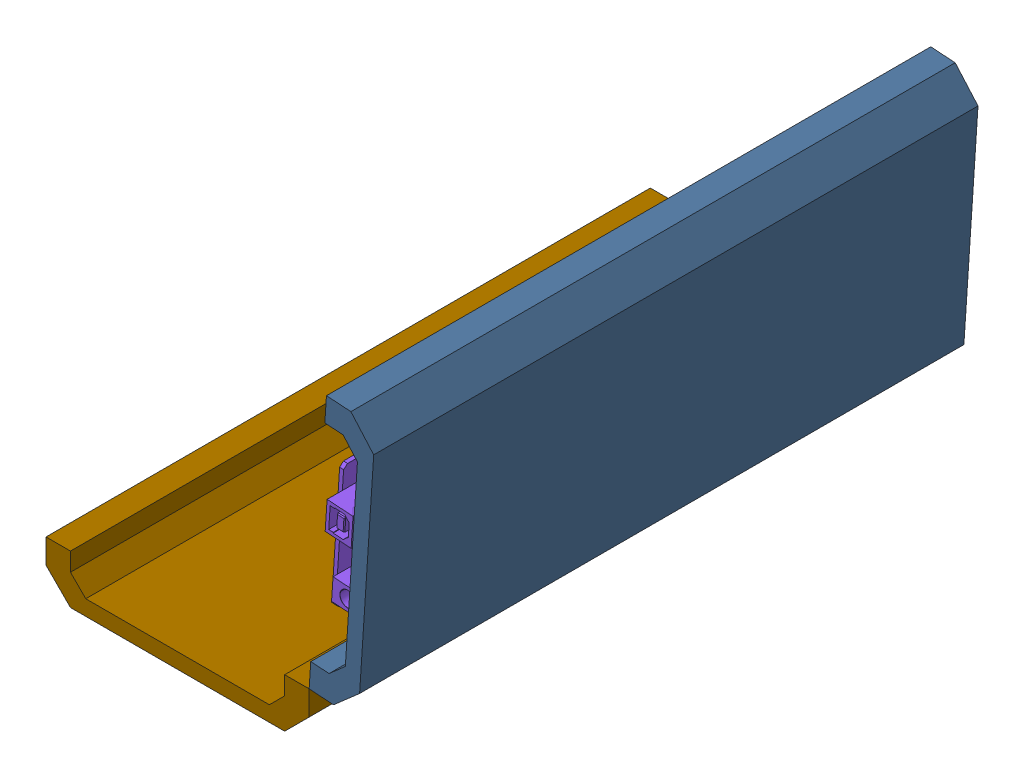
SolidWorks assembly blacktopTestJig, configuration Default. Lengths in mm.
Overall size (136.69 129.3 250.82).
19 component instances, 10 part files, 12 mates.
Components (placement in the parent):
- base-1: base [Default] at (-12.9077 -6.715 39.8526) size (63.5 1.59 96.52)
- MSP-EXP430G2ET-1: MSP-EXP430G2ET [Default] at (-12.9077 1.667 -16.0274) size (58.42 18.61 78.74)
- blacktop02.step-1: blacktop02.step [Default] at (-162.7677 0.335 -47.7774) x (1 0 0) z (0 1 0) size (50.8 33.02 10.45)
  - SOIC-8_3.9x4.9mm_P1.27mm.step-1: SOIC-8_3.9x4.9mm_P1.27mm.step [Default] at (159.385 -75.8825 1.65) x (0 1 0) z (0 0 1) size (6 4.9 1.75)
    - SOLID.step-1: SOLID.step [Default] at origin size (6 4.9 1.75)
  - TSSOP-28_4.4x9.7mm_P0.65mm.step-1: TSSOP-28_4.4x9.7mm_P0.65mm.step [Default] at (136.491 -75.89 1.65) x (0 -1 0) z (0 0 1) size (6.4 9.7 1.1)
    - SOLID-0.step-1: SOLID-0.step [Default] at origin size (6.4 9.7 1.1)
  - PinSocket_1x10_P2.54mm_Vertical.step-1: PinSocket_1x10_P2.54mm_Vertical.step [Default] at (172.72 -76.2 -0.05) x (-1 0 0) z (0 0 -1) size (2.54 25.4 10.1)
    - SOLID-1.step-1: SOLID-1.step [Default] at origin size (2.54 25.4 10.1)
  - PinSocket_1x10_P2.54mm_Vertical.step-2: PinSocket_1x10_P2.54mm_Vertical.step [Default] at (127 -76.2 -0.05) x (-1 0 0) z (0 0 -1) size (2.54 25.4 10.1)
    - SOLID-1.step-1: SOLID-1.step [Default] at origin size (2.54 25.4 10.1)
  - C_0603_1608Metric.step-1: C_0603_1608Metric.step [Default] at (158.355 -71.12 1.65) size (1.6 0.8 0.8)
    - SOLID-2.step-1: SOLID-2.step [Default] at origin size (1.6 0.8 0.8)
  - C_0603_1608Metric.step-2: C_0603_1608Metric.step [Default] at (141.5936 -71.12 1.65) x (-1 0 0) z (0 0 1) size (1.6 0.8 0.8)
    - SOLID-2.step-1: SOLID-2.step [Default] at origin size (1.6 0.8 0.8)
  - COMPOUND.step-1: COMPOUND.step [Default] at origin size (50.8 33.02 1.6)
- ArduinoMega-1: ArduinoMega [Default] at (45.9223 52.9564 120.3261) x (0 0 1) z (-0.99783 0.065837 0) size (107.95 53.42 12.95)
- CaseLower-1: CaseLower [Default] at (5.242 -1.7477 26.9005) size (109.22 20.32 250.82)
- CaseUpper-1: CaseUpper [Default] at (56.0378 57.4931 40.42) x (0.065837 0.99783 0) z (0 0 1) size (109.22 20.32 250.83)
Mates (geometry in assembly coordinates):
- Coincident1: coincident anti-aligned: line of base-1 through (11.2223 -6.715 -3.3274) axis (0 0 -1); line of MSP-EXP430G2ET-1 through (11.2223 -6.715 -28.7274) axis (0 0 1)
- Coincident2: coincident aligned: line of base-1 through (11.2223 -6.715 -3.3274) axis (-1 0 0); line of MSP-EXP430G2ET-1 through (11.2223 -6.715 -3.3274) axis (-1 0 0)
- Coincident3: coincident anti-aligned: line of base-1 through (11.2223 -6.715 52.5526) axis (0 0 -1); line of blacktop02.step-1/PinSocket_1x10_P2.54mm_Vertical.step-1/SOLID-1.step-1 through (11.2223 -6.715 27.1526) axis (0 0 1)
- Coincident4: coincident aligned: line of base-1 through (11.2223 -6.715 52.5526) axis (-1 0 0); line of blacktop02.step-1/PinSocket_1x10_P2.54mm_Vertical.step-1/SOLID-1.step-1 through (11.2223 -6.715 52.5526) axis (-1 0 0)
- Coincident5: coincident anti-aligned: plane of base-1 through (-42.1177 -8.3025 57.6326) normal (0 -1 0); plane of CaseLower-1 through (15.0323 -8.3025 -32.5374) normal (0 1 0)
- Concentric1: concentric aligned: circle of base-1; circle of CaseLower-1
- Concentric2: concentric aligned: circle of base-1; circle of CaseLower-1
- Coincident6: coincident aligned: line of CaseLower-1 through (41.7023 0.5875 -71.2724) axis (0 0 1); line of CaseUpper-1 through (41.7023 0.5875 -71.2724) axis (0 0 1)
- Coincident7: coincident: point of CaseLower-1; point of CaseUpper-1
- Parallel1: parallel anti-aligned: plane of ArduinoMega-1 through (44.1639 26.3063 171.1261) normal (0.99783 -0.065837 0); plane of CaseUpper-1 through (61.7458 92.1766 -71.2724) normal (-0.99783 0.065837 0)
- Parallel2: parallel aligned: line of ArduinoMega-1 through (42.6168 27.9357 171.1261) axis (0.065837 0.99783 0); line of CaseUpper-1 through (56.729 16.1419 179.5526) axis (0.065837 0.99783 0)
- Lock1: lock: unknown of ArduinoMega-1; unknown of CaseUpper-1
